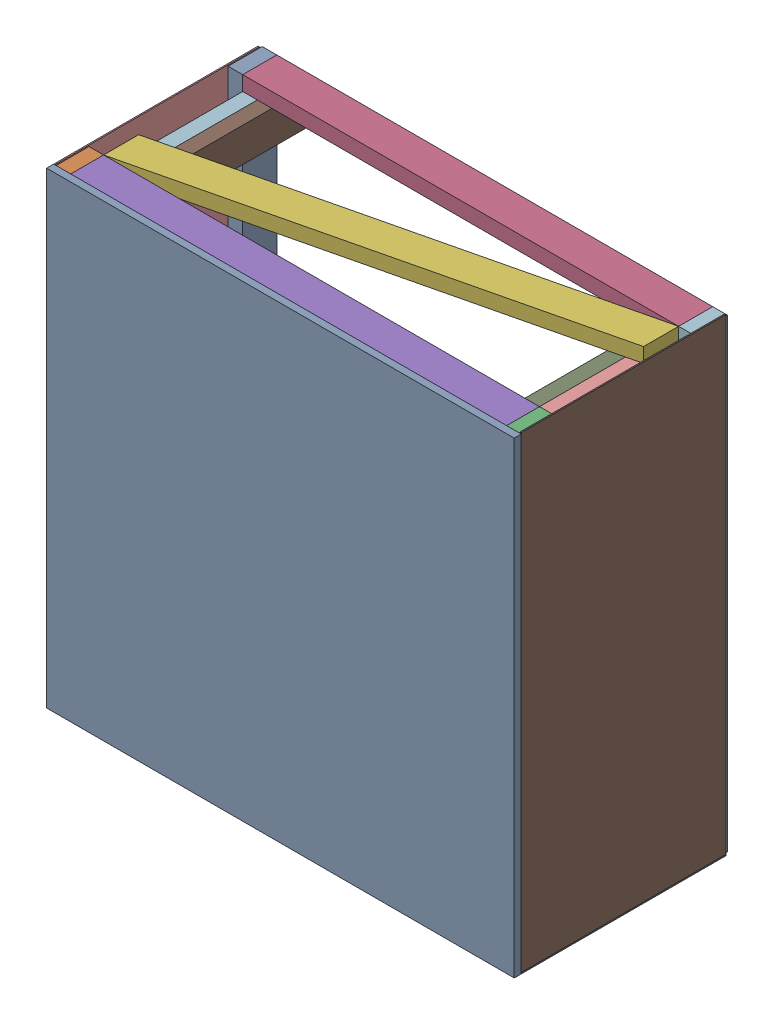
SolidWorks assembly TE-19102, configuration Default. Lengths in mm.
Overall size (1219.2 1222.38 558.8).
25 component instances, 6 part files, 85 mates.
Components (placement in the parent):
- TE-19102-04-1: TE-19102-04 [Default] at (-98.2347 1219.2 -52.3612) size (1219.2 1219.2 18.26)
- TE-19102-01-1: TE-19102-01 [Default] at (-625.1538 367.8748 -103.7264) x (1 0 0) z (0 1 0) size (38.1 88.9 1212.85)
- TE-19102-01-2: TE-19102-01 [Default] at (549.5962 367.8748 -103.7264) x (1 0 0) z (0 1 0) size (38.1 88.9 1212.85)
- TE-19102-02-1: TE-19102-02 [Default] at (532.6406 996.5248 -83.8758) x (0 1 0) z (-1 0 0) size (38.1 88.9 1136.65)
- TE-19102-02-2: TE-19102-02 [Default] at (532.6406 1580.7248 -83.8758) x (0 1 0) z (-1 0 0) size (38.1 88.9 1136.65)
- TE-19102-02-3: TE-19102-02 [Default] at (532.6406 405.9748 -83.8758) x (0 1 0) z (-1 0 0) size (38.1 88.9 1136.65)
- TE-19102-03-1: TE-19102-03 [Default] at (496.9206 467.1043 -592.9049) size (38.1 88.9 540.54)
- TE-19102-03-2: TE-19102-03 [Default] at (458.8206 467.1043 -592.9049) size (38.1 88.9 540.54)
- TE-19102-03-3: TE-19102-03 [Default] at (458.8206 1514.8543 -592.9049) size (38.1 88.9 540.54)
- TE-19102-03-4: TE-19102-03 [Default] at (496.9206 1514.8543 -592.9049) size (38.1 88.9 540.54)
- TE-19102-03-5: TE-19102-03 [Default] at (-563.5294 1514.8543 -592.9049) size (38.1 88.9 540.54)
- TE-19102-03-6: TE-19102-03 [Default] at (-601.6294 1514.8543 -592.9049) size (38.1 88.9 540.54)
- TE-19102-03-7: TE-19102-03 [Default] at (-563.5294 467.1043 -592.9049) size (38.1 88.9 540.54)
- TE-19102-03-8: TE-19102-03 [Default] at (-601.6294 467.1043 -592.9049) size (38.1 88.9 540.54)
- TE-19102-02-6: TE-19102-02 [Default] at (532.6406 405.9748 -535.5195) x (0 1 0) z (-1 0 0) size (38.1 88.9 1136.65)
- TE-19102-02-7: TE-19102-02 [Default] at (532.6406 1580.7248 -535.5195) x (0 1 0) z (-1 0 0) size (38.1 88.9 1136.65)
- TE-19102-06-1: TE-19102-06 [Default] at (-413.216 367.8748 -345.8808) x (1 0 0) z (0 1 0) size (1136.65 362.74 38.1)
- TE-19102-06-2: TE-19102-06 [Default] at (-413.216 1580.7248 -299.3853) x (1 0 0) z (0 -1 0) size (1136.65 362.74 38.1)
- TE-19102-06-3: TE-19102-06 [Default] at (532.6406 596.7683 -299.3853) x (0 1 0) z (1 0 0) size (1136.65 362.74 38.1)
- TE-19102-06-4: TE-19102-06 [Default] at (-604.0094 1351.8314 -299.3853) x (0 -1 0) z (-1 0 0) size (1136.65 362.74 38.1)
- TE-19102-05-1: TE-19102-05 [Default] at (-645.2844 367.8748 -585.7612) x (1 0 0) z (0 -1 0) size (1219.2 533.4 3.17)
- TE-19102-05-2: TE-19102-05 [Default] at (-645.2844 1583.8998 -52.3612) x (0 -1 0) z (1 0 0) size (1219.2 533.4 3.17)
- TE-19102-05-3: TE-19102-05 [Default] at (573.9156 367.8748 -52.3612) x (0 1 0) z (-1 0 0) size (1219.2 533.4 3.17)
- TE-19102-01-3: TE-19102-01 [Default] at (549.5962 367.8748 -555.3702) x (1 0 0) z (0 1 0) size (38.1 88.9 1212.85)
- TE-19102-01-4: TE-19102-01 [Default] at (-625.1538 1580.7248 -541.5396) x (1 0 0) z (0 -1 0) size (38.1 88.9 1212.85)
Mates (geometry in assembly coordinates):
- Coincident1: coincident: plane of TE-19102-04-1 through (-98.2347 1219.2 -52.3612) normal (0 0 -1); plane of TE-19102-01-1 through (-642.1094 1580.7248 -52.3612) normal (0 0 1)
- Coincident2: coincident: plane of TE-19102-04-1 through (-645.2844 1583.8998 -34.1049) normal (-1 0 0); plane of ? through (-645.2844 1577.5498 -141.2612) normal (-1 0 0)
- Coincident3: coincident: plane of TE-19102-04-1 through (-645.2844 364.6998 -34.1049) normal (0 -1 0); plane of ? through (-625.1538 364.6998 -103.7264) normal (0 -1 0)
- Coincident4: coincident: plane of TE-19102-04-1 through (-98.2347 1219.2 -52.3612) normal (0 0 -1); plane of TE-19102-01-2 through (532.6406 1580.7248 -52.3612) normal (0 0 1)
- Coincident6: coincident: plane of TE-19102-04-1 through (-645.2844 364.6998 -34.1049) normal (0 -1 0); plane of ? through (549.5962 364.6998 -103.7264) normal (0 -1 0)
- Coincident7: coincident: plane of assembly; plane of assembly; plane of TE-19102-01-2 through (532.6406 1580.7248 -141.2612) normal (-1 0 0); plane of TE-19102-02-3 through (532.6406 405.9748 -83.8758) normal (1 0 0)
- Coincident8: coincident: plane of TE-19102-04-1 through (-98.2347 1219.2 -52.3612) normal (0 0 -1); plane of TE-19102-02-3 through (-604.0094 367.8748 -52.3612) normal (0 0 1)
- Coincident9: coincident: plane of TE-19102-04-1 through (-645.2844 364.6998 -34.1049) normal (0 -1 0); plane of ? through (-600.8344 364.6998 -141.2612) normal (0 -1 0)
- Coincident10: coincident: plane of assembly; plane of assembly; plane of TE-19102-01-2 through (532.6406 1580.7248 -141.2612) normal (-1 0 0); plane of TE-19102-02-2 through (532.6406 1580.7248 -83.8758) normal (1 0 0)
- Coincident11: coincident: plane of TE-19102-04-1 through (-98.2347 1219.2 -52.3612) normal (0 0 -1); plane of TE-19102-02-2 through (-604.0094 1542.6248 -52.3612) normal (0 0 1)
- Coincident12: coincident: plane of TE-19102-04-1 through (-645.2844 1583.8998 -34.1049) normal (0 1 0); plane of ? through (-604.0094 1583.8998 -141.2612) normal (0 1 0)
- Coincident13: coincident: plane of assembly; plane of assembly; plane of TE-19102-01-2 through (532.6406 1580.7248 -141.2612) normal (-1 0 0); plane of TE-19102-02-1 through (532.6406 996.5248 -83.8758) normal (1 0 0)
- Coincident14: coincident: plane of TE-19102-04-1 through (-98.2347 1219.2 -52.3612) normal (0 0 -1); plane of TE-19102-02-1 through (-604.0094 958.4248 -52.3612) normal (0 0 1)
- Symmetric1: symmetric: plane of assembly; plane of assembly; plane of TE-19102-02-1 through (-604.0094 958.4248 -141.2612) normal (0 -1 0); plane of TE-19102-02-1 through (-604.0094 996.5248 -141.2612) normal (0 1 0); plane of assembly
- Coincident16: coincident: plane of TE-19102-04-1 through (-98.2347 1219.2 -52.3612) normal (0 0 -1); plane of TE-19102-03-1 through (496.9206 467.1043 -52.3612) normal (0 0 1)
- Coincident17: coincident: plane of TE-19102-04-1 through (-98.2347 1219.2 -52.3612) normal (0 0 -1); plane of TE-19102-03-2 through (458.8206 467.1043 -52.3612) normal (0 0 1)
- Coincident18: coincident: plane of TE-19102-04-1 through (-98.2347 1219.2 -52.3612) normal (0 0 -1); plane of TE-19102-03-4 through (496.9206 1514.8543 -52.3612) normal (0 0 1)
- Coincident19: coincident: plane of TE-19102-04-1 through (-98.2347 1219.2 -52.3612) normal (0 0 -1); plane of TE-19102-03-3 through (458.8206 1514.8543 -52.3612) normal (0 0 1)
- Coincident20: coincident: plane of TE-19102-04-1 through (-98.2347 1219.2 -52.3612) normal (0 0 -1); plane of TE-19102-03-8 through (-601.6294 467.1043 -52.3612) normal (0 0 1)
- Coincident21: coincident: plane of TE-19102-04-1 through (-98.2347 1219.2 -52.3612) normal (0 0 -1); plane of TE-19102-03-7 through (-563.5294 467.1043 -52.3612) normal (0 0 1)
- Coincident22: coincident: plane of TE-19102-04-1 through (-98.2347 1219.2 -52.3612) normal (0 0 -1); plane of TE-19102-03-6 through (-601.6294 1514.8543 -52.3612) normal (0 0 1)
- Coincident23: coincident: plane of TE-19102-04-1 through (-98.2347 1219.2 -52.3612) normal (0 0 -1); plane of TE-19102-03-5 through (-563.5294 1514.8543 -52.3612) normal (0 0 1)
- Coincident24: coincident: plane of assembly; plane of assembly; plane of TE-19102-01-2 through (532.6406 1580.7248 -141.2612) normal (-1 0 0); plane of TE-19102-03-1 through (532.6406 494.8748 -52.3612) normal (1 0 0)
- Coincident25: coincident: plane of assembly; plane of assembly; plane of TE-19102-03-1 through (494.5406 494.8748 -52.3612) normal (-1 0 0); plane of TE-19102-03-2 through (494.5406 494.8748 -52.3612) normal (1 0 0)
- Coincident26: coincident: plane of assembly; plane of assembly; plane of TE-19102-03-1 through (494.5406 405.9748 -52.3612) normal (0 -1 0); plane of TE-19102-03-2 through (456.4406 405.9748 -52.3612) normal (0 -1 0)
- Coincident27: coincident: plane of assembly; plane of assembly; plane of TE-19102-02-3 through (-604.0094 405.9748 -141.2612) normal (0 1 0); plane of TE-19102-03-1 through (494.5406 405.9748 -52.3612) normal (0 -1 0)
- Coincident28: coincident: plane of assembly; plane of assembly; plane of TE-19102-03-3 through (494.5406 1542.6248 -52.3612) normal (1 0 0); plane of TE-19102-03-4 through (494.5406 1542.6248 -52.3612) normal (-1 0 0)
- Coincident29: coincident: plane of assembly; plane of assembly; plane of TE-19102-03-3 through (456.4406 1542.6248 -52.3612) normal (0 1 0); plane of TE-19102-03-4 through (494.5406 1542.6248 -52.3612) normal (0 1 0)
- Coincident30: coincident: plane of assembly; plane of assembly; plane of TE-19102-01-2 through (532.6406 1580.7248 -141.2612) normal (-1 0 0); plane of TE-19102-03-4 through (532.6406 1542.6248 -52.3612) normal (1 0 0)
- Coincident31: coincident: plane of assembly; plane of assembly; plane of TE-19102-02-2 through (-604.0094 1542.6248 -141.2612) normal (0 -1 0); plane of TE-19102-03-3 through (456.4406 1542.6248 -52.3612) normal (0 1 0)
- Coincident32: coincident: plane of assembly; plane of assembly; plane of TE-19102-03-7 through (-565.9094 494.8748 -52.3612) normal (-1 0 0); plane of TE-19102-03-8 through (-565.9094 494.8748 -52.3612) normal (1 0 0)
- Coincident33: coincident: plane of assembly; plane of assembly; plane of TE-19102-03-7 through (-565.9094 405.9748 -52.3612) normal (0 -1 0); plane of TE-19102-03-8 through (-604.0094 405.9748 -52.3612) normal (0 -1 0)
- Coincident34: coincident: plane of assembly; plane of assembly; plane of TE-19102-02-3 through (-604.0094 405.9748 -141.2612) normal (0 1 0); plane of TE-19102-03-8 through (-604.0094 405.9748 -52.3612) normal (0 -1 0)
- Coincident35: coincident: plane of assembly; plane of assembly; plane of TE-19102-01-1 through (-604.0094 1580.7248 -141.2612) normal (1 0 0); plane of TE-19102-03-8 through (-604.0094 494.8748 -52.3612) normal (-1 0 0)
- Coincident36: coincident: plane of assembly; plane of assembly; plane of TE-19102-03-5 through (-565.9094 1542.6248 -52.3612) normal (-1 0 0); plane of TE-19102-03-6 through (-565.9094 1542.6248 -52.3612) normal (1 0 0)
- Coincident37: coincident: plane of assembly; plane of assembly; plane of TE-19102-03-5 through (-565.9094 1542.6248 -52.3612) normal (0 1 0); plane of TE-19102-03-6 through (-604.0094 1542.6248 -52.3612) normal (0 1 0)
- Coincident38: coincident: plane of assembly; plane of assembly; plane of TE-19102-01-1 through (-604.0094 1580.7248 -141.2612) normal (1 0 0); plane of TE-19102-03-6 through (-604.0094 1542.6248 -52.3612) normal (-1 0 0)
- Coincident39: coincident: plane of assembly; plane of assembly; plane of TE-19102-02-2 through (-604.0094 1542.6248 -141.2612) normal (0 -1 0); plane of TE-19102-03-5 through (-565.9094 1542.6248 -52.3612) normal (0 1 0)
- Coincident41: coincident: plane of assembly; plane of assembly; plane of TE-19102-03-7 through (-563.5294 467.1043 -592.9049) normal (0 0 -1); plane of TE-19102-02-6 through (-604.0094 367.8748 -592.9049) normal (0 0 -1)
- Coincident44: coincident: plane of assembly; plane of assembly; plane of TE-19102-03-8 through (-604.0094 405.9748 -52.3612) normal (0 -1 0); plane of TE-19102-02-6 through (-604.0094 405.9748 -592.9049) normal (0 1 0)
- Coincident55: coincident: plane of assembly; plane of assembly; plane of TE-19102-03-2 through (456.4406 405.9748 -52.3612) normal (0 -1 0); plane of TE-19102-06-1 through (-413.216 405.9748 -345.8808) normal (0 1 0)
- Coincident59: coincident: plane of assembly; plane of assembly; plane of TE-19102-03-8 through (-604.0094 494.8748 -52.3612) normal (-1 0 0); plane of TE-19102-06-4 through (-604.0094 1351.8314 -299.3853) normal (1 0 0)
- Coincident63: coincident: plane of assembly; plane of assembly; plane of TE-19102-03-1 through (532.6406 494.8748 -52.3612) normal (1 0 0); plane of TE-19102-06-3 through (532.6406 596.7683 -299.3853) normal (-1 0 0)
- Coincident66: coincident: plane of assembly; plane of assembly; plane of TE-19102-03-6 through (-604.0094 1542.6248 -52.3612) normal (0 1 0); plane of TE-19102-06-2 through (-413.216 1542.6248 -299.3853) normal (0 -1 0)
- Coincident76: coincident: plane of ? through (-600.8344 491.6998 -52.3612) normal (0 1 0); plane of ? through (-600.8344 491.6998 -592.9049) normal (0 -1 0)
- Coincident83: coincident: plane of assembly; plane of assembly; plane of TE-19102-03-4 through (532.6406 1542.6248 -52.3612) normal (1 0 0); plane of TE-19102-06-2 through (532.6406 1542.6248 -412.6068) normal (1 0 0)
- Coincident84: coincident: line of ?; line of ? through (535.8156 1542.6248 -592.9049) axis (0 1 0)
- Coincident85: coincident: plane of assembly; plane of assembly; plane of TE-19102-03-6 through (-604.0094 1542.6248 -52.3612) normal (0 1 0); plane of TE-19102-06-4 through (-642.1094 1542.6248 -232.6592) normal (0 1 0)
- Coincident86: coincident: plane of ? through (-598.4544 463.9293 -592.9049) normal (0 0 -1); line of ? through (-619.8844 405.9748 -592.9049) axis (1 0 0)
- Coincident87: coincident: plane of assembly; plane of assembly; plane of TE-19102-03-1 through (532.6406 494.8748 -52.3612) normal (1 0 0); plane of TE-19102-06-1 through (532.6406 405.9748 -232.6592) normal (1 0 0)
- Coincident88: coincident: plane of ? through (-598.4544 463.9293 -592.9049) normal (0 0 -1); line of ? through (-600.8344 402.7998 -592.9049) axis (0 -1 0)
- Coincident89: coincident: plane of assembly; plane of assembly; plane of TE-19102-03-1 through (494.5406 405.9748 -52.3612) normal (0 -1 0); plane of TE-19102-06-3 through (570.7406 405.9748 -232.6592) normal (0 -1 0)
- Coincident90: coincident: plane of ? through (500.0956 1514.8543 -592.9049) normal (0 0 -1); line of ? through (554.8656 1539.4498 -592.9049) axis (-1 0 0)
- Coincident91: coincident: plane of assembly; plane of assembly; plane of TE-19102-01-1 through (-604.0094 1580.7248 -141.2612) normal (1 0 0); plane of TE-19102-02-3 through (-604.0094 405.9748 -83.8758) normal (-1 0 0)
- Distance1: distance = 3.175 mm: plane of TE-19102-01-1 through (-642.1094 1580.7248 -141.2612) normal (-1 0 0); plane of TE-19102-04-1 through (-645.2844 1583.8998 -34.1049) normal (-1 0 0)
- Coincident93: coincident: plane of assembly; plane of assembly; plane of TE-19102-01-2 through (549.5962 1580.7248 -103.7264) normal (0 1 0); plane of TE-19102-02-2 through (-604.0094 1580.7248 -141.2612) normal (0 1 0)
- Distance2: distance = 3.175 mm: plane of TE-19102-02-2 through (-604.0094 1580.7248 -141.2612) normal (0 1 0); plane of TE-19102-04-1 through (-645.2844 1583.8998 -34.1049) normal (0 1 0)
- Coincident95: coincident: plane of assembly; line of assembly; plane of TE-19102-02-3 through (-604.0094 367.8748 -141.2612) normal (0 0 -1); line of TE-19102-06-1 through (532.6406 405.9748 -141.2612) axis (0 -1 0)
- Coincident96: coincident: plane of assembly; line of assembly; plane of TE-19102-01-2 through (532.6406 1580.7248 -141.2612) normal (0 0 -1); line of TE-19102-06-3 through (570.7406 405.9748 -141.2612) axis (-1 0 0)
- Distance5: distance = 3.175 mm: plane of TE-19102-02-3 through (-604.0094 367.8748 -141.2612) normal (0 -1 0); plane of TE-19102-04-1 through (-645.2844 364.6998 -34.1049) normal (0 -1 0)
- Coincident100: coincident: plane of assembly; plane of assembly; plane of TE-19102-01-1 through (-625.1538 367.8748 -103.7264) normal (0 -1 0); plane of TE-19102-02-3 through (-604.0094 367.8748 -141.2612) normal (0 -1 0)
- Coincident103: coincident: plane of assembly; line of assembly; plane of TE-19102-01-1 through (-642.1094 1580.7248 -141.2612) normal (0 0 -1); line of TE-19102-06-4 through (-642.1094 1542.6248 -141.2612) axis (1 0 0)
- Coincident104: coincident: plane of assembly; line of assembly; plane of TE-19102-01-1 through (-642.1094 1580.7248 -141.2612) normal (0 0 -1); line of TE-19102-06-2 through (-604.0094 1542.6248 -141.2612) axis (0 1 0)
- Coincident107: coincident: plane of assembly; plane of assembly; plane of TE-19102-01-1 through (-642.1094 1580.7248 -141.2612) normal (-1 0 0); plane of TE-19102-05-2 through (-642.1094 1583.8998 -52.3612) normal (1 0 0)
- Coincident108: coincident: plane of TE-19102-04-1 through (-98.2347 1219.2 -52.3612) normal (0 0 -1); plane of TE-19102-05-2 through (-642.1094 1583.8998 -52.3612) normal (0 0 1)
- Coincident109: coincident: plane of TE-19102-04-1 through (-645.2844 364.6998 -34.1049) normal (0 -1 0); plane of TE-19102-05-2 through (-642.1094 364.6998 -52.3612) normal (0 -1 0)
- Coincident110: coincident: plane of assembly; plane of assembly; plane of TE-19102-02-3 through (-604.0094 367.8748 -141.2612) normal (0 -1 0); plane of TE-19102-05-1 through (-645.2844 367.8748 -585.7612) normal (0 1 0)
- Coincident111: coincident: plane of TE-19102-04-1 through (-98.2347 1219.2 -52.3612) normal (0 0 -1); plane of TE-19102-05-1 through (-645.2844 364.6998 -52.3612) normal (0 0 1)
- Coincident112: coincident: plane of assembly; plane of assembly; plane of TE-19102-05-1 through (-645.2844 364.6998 -585.7612) normal (-1 0 0); plane of TE-19102-05-2 through (-645.2844 1583.8998 -52.3612) normal (-1 0 0)
- Coincident113: coincident: plane of TE-19102-03-1 through (532.6406 494.8748 -52.3612) normal (1 0 0); plane of ? through (532.6406 353.7699 -52.3612) normal (-1 0 0)
- Coincident114: coincident: plane of TE-19102-04-1 through (-98.2347 1219.2 -52.3612) normal (0 0 -1); plane of TE-19102-05-3 through (570.7406 367.8748 -52.3612) normal (0 0 1)
- Coincident115: coincident: plane of assembly; plane of assembly; plane of TE-19102-01-2 through (570.7406 1580.7248 -141.2612) normal (1 0 0); plane of TE-19102-05-3 through (570.7406 367.8748 -52.3612) normal (-1 0 0)
- Coincident116: coincident: plane of assembly; plane of assembly; plane of TE-19102-05-1 through (-645.2844 367.8748 -585.7612) normal (0 1 0); plane of TE-19102-05-3 through (570.7406 367.8748 -52.3612) normal (0 -1 0)
- Coincident119: coincident: plane of assembly; plane of assembly; plane of TE-19102-03-1 through (496.9206 467.1043 -592.9049) normal (0 0 -1); plane of TE-19102-02-6 through (-604.0094 367.8748 -592.9049) normal (0 0 -1)
- Coincident120: coincident: plane of assembly; plane of assembly; plane of TE-19102-03-2 through (456.4406 405.9748 -52.3612) normal (0 -1 0); plane of TE-19102-02-6 through (-604.0094 405.9748 -592.9049) normal (0 1 0)
- Coincident126: coincident: plane of assembly; plane of assembly; plane of TE-19102-03-1 through (532.6406 494.8748 -52.3612) normal (1 0 0); plane of TE-19102-02-6 through (532.6406 405.9748 -535.5195) normal (1 0 0)
- Coincident127: coincident: plane of assembly; plane of assembly; plane of TE-19102-03-3 through (456.4406 1542.6248 -52.3612) normal (0 1 0); plane of TE-19102-02-7 through (-604.0094 1542.6248 -592.9049) normal (0 -1 0)
- Coincident128: coincident: plane of assembly; plane of assembly; plane of TE-19102-03-4 through (532.6406 1542.6248 -52.3612) normal (1 0 0); plane of TE-19102-02-7 through (532.6406 1580.7248 -535.5195) normal (1 0 0)
- Coincident129: coincident: plane of assembly; plane of assembly; plane of TE-19102-03-4 through (496.9206 1514.8543 -592.9049) normal (0 0 -1); plane of TE-19102-02-7 through (-604.0094 1542.6248 -592.9049) normal (0 0 -1)
- Coincident130: coincident: plane of TE-19102-03-4 through (532.6406 1542.6248 -52.3612) normal (1 0 0); plane of ? through (514.1209 1548.1215 -593.3789) normal (-1 0 0)
- Coincident131: coincident: plane of TE-19102-03-4 through (496.9206 1514.8543 -592.9049) normal (0 0 -1); plane of ? through (514.1209 1548.1215 -593.3789) normal (0 0 -1)
- Coincident133: coincident: plane of assembly; plane of assembly; plane of TE-19102-03-6 through (-604.0094 1542.6248 -52.3612) normal (-1 0 0); plane of TE-19102-01-4 through (-604.0094 367.8748 -504.0049) normal (1 0 0)
- Coincident135: coincident: plane of assembly; plane of assembly; plane of TE-19102-03-6 through (-601.6294 1514.8543 -592.9049) normal (0 0 -1); plane of TE-19102-01-4 through (-642.1094 367.8748 -592.9049) normal (0 0 -1)
- Coincident136: coincident: plane of assembly; plane of assembly; plane of TE-19102-02-7 through (-604.0094 1580.7248 -592.9049) normal (0 1 0); plane of TE-19102-01-4 through (-625.1538 1580.7248 -541.5396) normal (0 1 0)
- Coincident137: coincident: plane of assembly; plane of assembly; plane of TE-19102-02-7 through (-604.0094 1580.7248 -592.9049) normal (0 1 0); plane of TE-19102-01-3 through (549.5962 1580.7248 -555.3702) normal (0 1 0)
